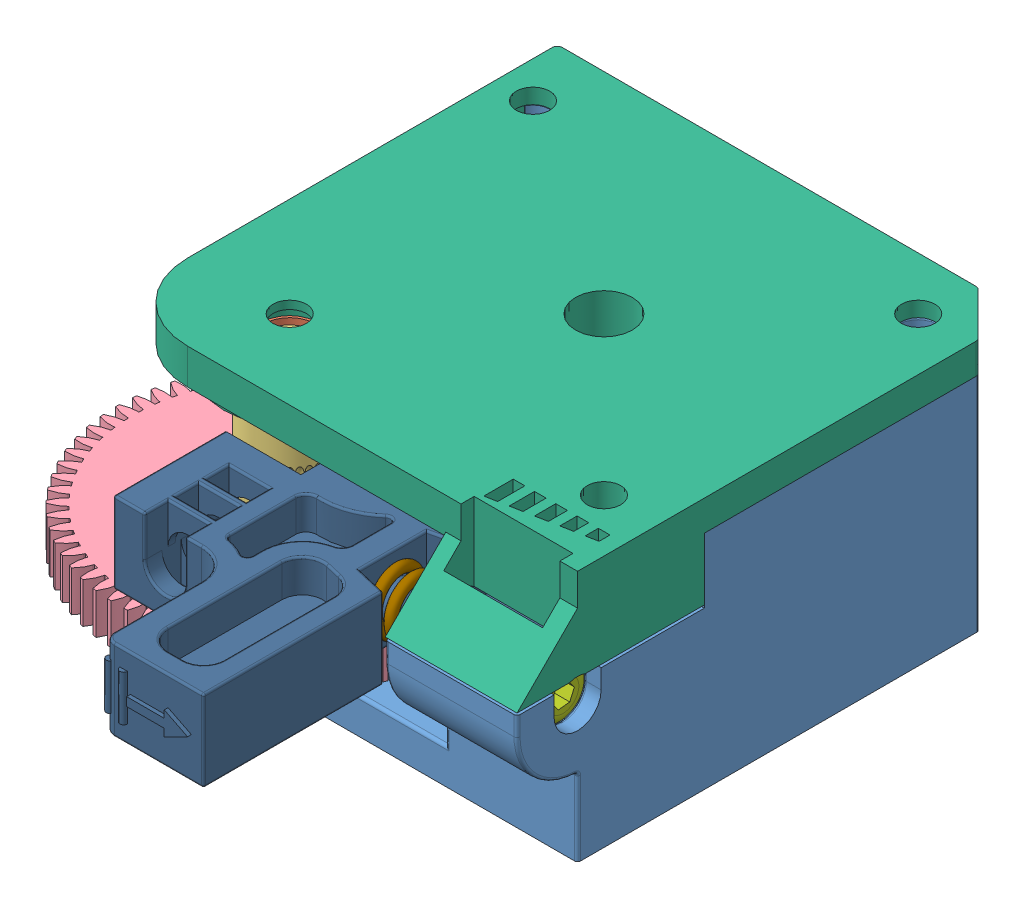
SolidWorks assembly e3d titan, configuration Default. Lengths in mm.
Overall size (60.24 25.35 66.08).
14 component instances, 13 part files, 0 mates.
Components (placement in the parent):
- E3D_Titan_Base-1: E3D_Titan_Base [Default] at origin size (46 23.41 49.98)
- 9x5x3mm bearing-1: 9x5x3mm bearing [Default] at (-15.5 4 15.5) x (0.988909 0 0.148526) z (0 -1 0) size (9 9 3)
- hobbed wheel-1: hobbed wheel [Default] at (-15.5 1.6 15.5) x (-0.707107 0 0.707107) z (0 1 0) size (8.6 8.58 20.6)
- filament gear-1: filament gear [Default] at (-15.5 8.55 15.5) x (-0.707107 0 -0.707107) z (0 -1 0) size (34 34 4)
- motor gear-1: motor gear [Default] at (0 8.55 0) x (0.707107 0 0.707107) z (0 -1 0) size (11.99 11.99 9)
- cover-1: cover [Default] at (0 24.9 0) x (1 0 0) z (0 0 -1) size (46 9.13 49.98)
- 9x5x3mm bearing-2: 9x5x3mm bearing [Default] at (-15.5 22.8 15.5) x (0.922034 0 0.38711) z (0 -1 0) size (9 9 3)
- m3x8-1: m3x8 [Default] at (17.599 13.6 23.3) x (0 0.404015 0.914752) z (0 0.914752 -0.404015) size (5.69 9.65 5.69)
- M3 nut-1: M3 nut [Default] at (15.913 13.6 23.3) x (0 1 0) z (0 0 1) size (6.19 2.71 6.57)
- idler spring-1: idler spring [Default] at (13.5 13.6 23.3) x (0 -0.157848 0.987463) z (-1 0 0) size (6.43 6.45 12.02)
- tensioner-1: tensioner [Default] at (0 13.6 0) x (0 -1 0) z (0 0 1) size (8.2 21.54 50.88)
- idler bearing pin-1: idler bearing pin [Default] at (-5.5 9.6 15.5) x (0.997492 0 0.070785) z (0 1 0) size (3.04 3.15 9)
- idler bearing-1: idler bearing [Default] at (-5.5 13.6 15.5) x (1 0 0) z (0 1 0) size (10 10 4)
- guide tube-1: guide tube [Default] at (-10.9 13.6 -7.9) x (-1 0 0) z (0 0 1) size (10.9 16.1 22.25)
